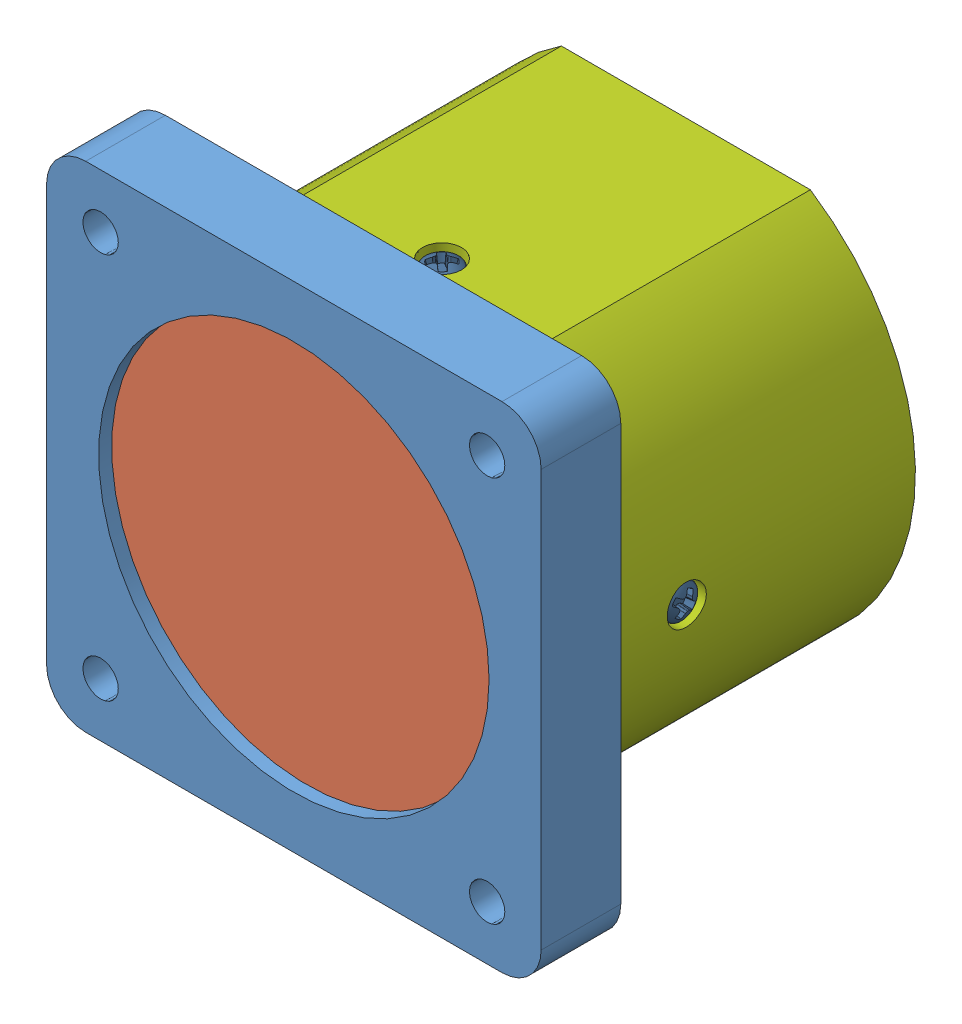
SolidWorks assembly Airspeed Indicator, configuration Default. Lengths in mm.
Overall size (60.32 60.32 47.82).
23 component instances, 13 part files, 54 mates.
Components (placement in the parent):
- Airspeed Indicator Bezel-1: Airspeed Indicator Bezel [Default] at origin size (60.32 60.32 9.72)
- Airspeed Indicator Cover Glass-1: Airspeed Indicator Cover Glass [Default] at (0 0 6.5405) size (49.91 49.91 1.59)
- Airspeed Indicator Dial Face Spacer-1: Airspeed Indicator Dial Face Spacer [Default] at (0 0 1.778) size (49.91 49.91 4.76)
- Airspeed Indicator Dial Face-1: Airspeed Indicator Dial Face [Default] at (0 0 0.1905) size (47.65 47.65 1.59)
- Airspeed Indicator Stepper Mount-1: Airspeed Indicator Stepper Mount [Default] at (0 0 0.1905) x (0 -1 0) z (0 0 -1) size (44.93 49.4 18.35)
- Airspeed Indicator Pointer-1: Airspeed Indicator Pointer [Default] at (0 0 3.3655) x (0.511521 -0.859271 0) z (0 0 1) size (3.17 30.16 0.76)
- Airspeed Indicator Case-1: Airspeed Indicator Case [Connector Down] x (-1 0 0) z (0 0 -1) size (56.01 51.53 38.1)
- VID29-02-1: VID29-02 [Default] at (0 -6 -13.8225) x (-1 0 0) z (0 1 0) size (31.7 22.35 29.3)
- MD-40PL100-1: MD-40PL100 [Default] at (0 0 -34.925) x (0 0 -1) z (1 0 0) size (21.05 14 25)
- 90272A077_ZINC-PLTD STL PAN HEAD PHILLIPS MACHINE SCREW_2-56 X .250-1: 90272A077_ZINC-PLTD STL PAN HEAD PHILLIPS MACHINE SCREW_2-56 X .250 [90272A077] at (-10.0394 -17.3887 -10.2108) x (-0.759966 0.438766 -0.479517) z (-0.5 -0.866025 0) size (4.24 4.24 7.94)
- 90272A077_ZINC-PLTD STL PAN HEAD PHILLIPS MACHINE SCREW_2-56 X .250-4: 90272A077_ZINC-PLTD STL PAN HEAD PHILLIPS MACHINE SCREW_2-56 X .250 [90272A077] at (0 15.6058 -8.3495) x (-0.738734 0 -0.673998) z (0 1 0) size (4.24 4.24 7.94)
- 90272A077_ZINC-PLTD STL PAN HEAD PHILLIPS MACHINE SCREW_2-56 X .250-3: 90272A077_ZINC-PLTD STL PAN HEAD PHILLIPS MACHINE SCREW_2-56 X .250 [90272A077] at (20.0787 0 -10.2108) x (0 0.846222 -0.532831) z (1 0 0) size (4.24 4.24 7.94)
- 93365A110_BRASS HEAT-SET INSERT FOR PLASTICS_2-56-1: 93365A110_BRASS HEAT-SET INSERT FOR PLASTICS_2-56 [Default] at (-12.3508 -21.3921 -10.0203) x (0.855214 -0.493758 -0.157515) z (-0.136412 0.078758 -0.987517) size (3.58 3.09 3.58)
- 93365A110_BRASS HEAT-SET INSERT FOR PLASTICS_2-56-2: 93365A110_BRASS HEAT-SET INSERT FOR PLASTICS_2-56 [Default] at (0 20.2286 -8.3495) x (-0.749902 0 0.661549) z (-0.661549 0 -0.749902) size (3.58 3.09 3.58)
- 93365A110_BRASS HEAT-SET INSERT FOR PLASTICS_2-56-3: 93365A110_BRASS HEAT-SET INSERT FOR PLASTICS_2-56 [Default] at (24.7015 0 -10.0203) x (0 0.487086 -0.873354) z (0 -0.873354 -0.487086) size (3.58 3.09 3.58)
- 93365A102 - INSERT, 0-80, BRASS, FOR PLASTICS-1: 93365A102 - INSERT, 0-80, BRASS, FOR PLASTICS [Default] at (-13.5 -6 -7.1105) x (0 1 0) z (-1 0 0) size (3.58 3.01 3.58)
- 93365A102 - INSERT, 0-80, BRASS, FOR PLASTICS-2: 93365A102 - INSERT, 0-80, BRASS, FOR PLASTICS [Default] at (13.5 -6 -7.1105) x (-0.158553 0.987351 0) z (-0.987351 -0.158553 0) size (3.58 3.01 3.58)
- 91772A064 - PHS, 0-80 x .4375, 18-8-1: 91772A064 - PHS, 0-80 x .4375, 18-8 [91772A064] at (-13.5 -6 -3.01) x (-1 0 0) z (0 0 -1) size (2.95 2.95 12.24)
- 91772A064 - PHS, 0-80 x .4375, 18-8-2: 91772A064 - PHS, 0-80 x .4375, 18-8 [91772A064] at (13.5 -6 -3.01) x (-0.987351 -0.158553 0) z (0 0 -1) size (2.95 2.95 12.24)
- 93365A102 - INSERT, 0-80, BRASS, FOR PLASTICS-4: 93365A102 - INSERT, 0-80, BRASS, FOR PLASTICS [Default] at (-9.5 0 -34.925) x (-0.015308 0.999883 0) z (0.999883 0.015308 0) size (3.58 3.01 3.58)
- 93365A102 - INSERT, 0-80, BRASS, FOR PLASTICS-6: 93365A102 - INSERT, 0-80, BRASS, FOR PLASTICS [Default] at (9.5 0 -34.925) x (-0.188703 0.982034 0) z (0.982034 0.188703 0) size (3.58 3.01 3.58)
- 91772A064 - PHS, 0-80 x .4375, 18-8-4: 91772A064 - PHS, 0-80 x .4375, 18-8 [91772A064] at (-9.5 0 -38.0375) x (-0.949722 0.313094 0) z (0 0 1) size (2.95 2.95 12.24)
- 91772A064 - PHS, 0-80 x .4375, 18-8-6: 91772A064 - PHS, 0-80 x .4375, 18-8 [91772A064] at (9.5 0 -38.0375) x (-0.902124 0.431476 0) z (0 0 1) size (2.95 2.95 12.24)
Mates (geometry in assembly coordinates):
- InPlace1: in place: plane of Airspeed Indicator Bezel-1 through (0 0 0) normal (0 0 1); moOrthogonalPlaneRef_w of Airspeed Indicator Bezel-1 through (0 0 0) normal (0 1 0); plane of Airspeed Indicator Bezel-1 through (0 0 0) normal (1 0 0); unknown of Airspeed Indicator Bezel-1
- Coincident1: coincident: plane of Airspeed Indicator Bezel-1; plane of assembly
- Coincident2: coincident: plane of Airspeed Indicator Bezel-1 through (0 0 0) normal (0 1 0); moOrthogonalPlaneRef_w of assembly
- Coincident3: coincident: plane of Airspeed Indicator Bezel-1 through (0 0 0) normal (1 0 0); moOrthogonalPlaneRef_w of assembly
- Concentric1: concentric: cylinder of Airspeed Indicator Bezel-1 through (0 0 81.3779) axis (0 0 -1) radius 25.3365; cylinder of Airspeed Indicator Cover Glass-1 through (0 0 8.128) axis (0 0 -1) radius 24.9555
- Coincident1: coincident: plane of Airspeed Indicator Bezel-1 through (0 0 8.128) normal (0 0 -1); plane of Airspeed Indicator Cover Glass-1 through (0 0 8.128) normal (0 0 1)
- Concentric2: concentric: cylinder of Airspeed Indicator Bezel-1 through (0 0 81.3779) axis (0 0 -1) radius 25.3365; cylinder of Airspeed Indicator Dial Face Spacer-1 through (0 0 6.5405) axis (0 0 -1) radius 24.9555
- Coincident2: coincident: plane of Airspeed Indicator Cover Glass-1 through (0 0 6.5405) normal (0 0 -1); plane of Airspeed Indicator Dial Face Spacer-1 through (0 0 6.5405) normal (0 0 1)
- Concentric5: concentric: cylinder of Airspeed Indicator Bezel-1 through (0 0 81.3779) axis (0 0 -1) radius 25.3365; cylinder of Airspeed Indicator Dial Face-1 through (0 0 1.778) axis (0 0 -1) radius 23.8252
- Parallel1: parallel: plane of Airspeed Indicator Bezel-1 through (30.1625 0 9.7155) normal (1 0 0); plane of Airspeed Indicator Dial Face-1 through (0 0 0.1905) normal (1 0 0)
- Concentric9: concentric: cylinder of Airspeed Indicator Bezel-1 through (0 0 81.3779) axis (0 0 -1) radius 25.3365; cylinder of Airspeed Indicator Stepper Mount-1 through (0 0 -72.238) axis (0 0 1) radius 24.7015
- Coincident7: coincident: plane of Airspeed Indicator Dial Face-1 through (0 0 0.1905) normal (0 0 -1); plane of Airspeed Indicator Stepper Mount-1 through (0 0 0.1905) normal (0 0 1)
- Parallel2: parallel: plane of Airspeed Indicator Bezel-1 through (0 30.1625 9.7155) normal (0 1 0); plane of Airspeed Indicator Stepper Mount-1 through (0 0 0.1905) normal (0 -1 0)
- Distance1: distance = 1.5875 mm: plane of Airspeed Indicator Pointer-1 through (0 0 3.3655) normal (0 0 -1); plane of Airspeed Indicator Dial Face-1 through (0 0 1.778) normal (0 0 1)
- Coincident13: coincident: plane of Airspeed Indicator Dial Face Spacer-1 through (0 0 1.778) normal (0 0 -1); plane of Airspeed Indicator Dial Face-1 through (0 0 1.778) normal (0 0 1)
- InPlace2: in place: plane of Airspeed Indicator Bezel-1 through (0 0 1.5875) normal (0 0 -1); plane of ? through (0 0 1.5875) normal (0 0 -1); plane of Airspeed Indicator Bezel-1 through (0 0 1.5875) normal (0 0 -1); unknown of ?; plane of Airspeed Indicator Bezel-1 through (0 0 1.5875) normal (0 0 -1); plane of ? through (0 0 1.5875) normal (-1 0 0); plane of Airspeed Indicator Bezel-1 through (0 0 0) normal (0 0 -1); unknown of Airspeed Indicator Case-1
- Coincident14: coincident: plane of Airspeed Indicator Bezel-1; plane of Airspeed Indicator Case-1
- Coincident15: coincident: moOrthogonalPlaneRef_w of Airspeed Indicator Bezel-1 through (0 0 0) normal (0 1 0); plane of Airspeed Indicator Case-1 through (0 0 0) normal (0 1 0)
- Coincident16: coincident: moOrthogonalPlaneRef_w of Airspeed Indicator Bezel-1 through (0 0 0) normal (1 0 0); plane of Airspeed Indicator Case-1 through (0 0 0) normal (-1 0 0)
- Concentric43: concentric: cylinder of Airspeed Indicator Case-1 through (-14.0017 -24.2517 -10.2108) axis (-0.5 -0.866025 0) radius 2.3813; cylinder of 90272A077_ZINC-PLTD STL PAN HEAD PHILLIPS MACHINE SCREW_2-56 X .250-1 through (-10.0394 -17.3887 -10.2108) axis (0.5 0.866025 0) radius 2.1209
- Coincident55: coincident: plane of Airspeed Indicator Case-1 through (-13.2143 -22.8879 -11.5633) normal (-0.5 -0.866025 0); plane of 90272A077_ZINC-PLTD STL PAN HEAD PHILLIPS MACHINE SCREW_2-56 X .250-1 through (-13.2143 -22.8879 -10.2108) normal (0.5 0.866025 0)
- Concentric44: concentric: cylinder of Airspeed Indicator Case-1 through (0 23.5306 -8.3495) axis (0 1 0) radius 2.3813; cylinder of 90272A077_ZINC-PLTD STL PAN HEAD PHILLIPS MACHINE SCREW_2-56 X .250-4 through (0 15.6058 -8.3495) axis (0 -1 0) radius 2.1209
- Coincident56: coincident: plane of Airspeed Indicator Case-1 through (-1.3526 21.9558 -8.3495) normal (0 1 0); plane of 90272A077_ZINC-PLTD STL PAN HEAD PHILLIPS MACHINE SCREW_2-56 X .250-4 through (0 21.9558 -8.3495) normal (0 -1 0)
- Coincident57: coincident: plane of Airspeed Indicator Case-1 through (26.4287 1.3526 -10.2108) normal (1 0 0); plane of 90272A077_ZINC-PLTD STL PAN HEAD PHILLIPS MACHINE SCREW_2-56 X .250-3 through (26.4287 0 -10.2108) normal (-1 0 0)
- Concentric46: concentric: cone of Airspeed Indicator Stepper Mount-1 through (-12.3508 -21.3921 -10.0203) axis (0.5 0.866025 0); cone of 93365A110_BRASS HEAT-SET INSERT FOR PLASTICS_2-56-1 through (-11.7958 -20.4309 -10.0203) axis (0.5 0.866025 0)
- Coincident58: coincident: plane of Airspeed Indicator Stepper Mount-1 through (-12.3508 -21.3921 -10.0203) normal (-0.5 -0.866025 0); plane of 93365A110_BRASS HEAT-SET INSERT FOR PLASTICS_2-56-1 through (-13.8822 -20.508 -9.7382) normal (-0.5 -0.866025 0)
- Concentric47: concentric: cone of Airspeed Indicator Stepper Mount-1 through (0 20.2286 -8.3495) axis (0 -1 0); cone of 93365A110_BRASS HEAT-SET INSERT FOR PLASTICS_2-56-2 through (0 19.1186 -8.3495) axis (0 -1 0)
- Concentric48: concentric: cone of Airspeed Indicator Stepper Mount-1 through (24.7015 0 -10.0203) axis (-1 0 0); cone of 93365A110_BRASS HEAT-SET INSERT FOR PLASTICS_2-56-3 through (23.5915 0 -10.0203) axis (-1 0 0)
- Coincident60: coincident: plane of Airspeed Indicator Stepper Mount-1 through (24.7015 0 -10.0203) normal (1 0 0); plane of 93365A110_BRASS HEAT-SET INSERT FOR PLASTICS_2-56-3 through (24.7015 -0.8722 -8.4564) normal (1 0 0)
- Concentric49: concentric: cylinder of Airspeed Indicator Dial Face-1 through (0 0 0.1905) axis (0 0 1) radius 0.7937; cylinder of VID29-02-1 through (0 0 -7.4225) axis (0 0 -1) radius 0.5
- Coincident61: coincident: plane of Airspeed Indicator Pointer-1 through (0 0 4.1275) normal (0 0 1); plane of VID29-02-1 through (0 0 4.1275) normal (0 0 1)
- Concentric50: concentric: cone of Airspeed Indicator Stepper Mount-1 through (-13.5 -6 -7.1105) axis (0 0 1); cone of 93365A102 - INSERT, 0-80, BRASS, FOR PLASTICS-1 through (-13.5 -6 -6.0005) axis (0 0 1)
- Coincident62: coincident: plane of Airspeed Indicator Stepper Mount-1 through (-13.5 -6 -7.1105) normal (0 0 -1); plane of 93365A102 - INSERT, 0-80, BRASS, FOR PLASTICS-1 through (-13.5 -7.7907 -7.1105) normal (0 0 -1)
- Concentric51: concentric: cone of Airspeed Indicator Stepper Mount-1 through (13.5 -6 -7.1105) axis (0 0 1); cone of 93365A102 - INSERT, 0-80, BRASS, FOR PLASTICS-2 through (13.5 -6 -6.0005) axis (0 0 1)
- Coincident63: coincident: plane of Airspeed Indicator Stepper Mount-1 through (13.5 -6 -7.1105) normal (0 0 -1); plane of 93365A102 - INSERT, 0-80, BRASS, FOR PLASTICS-2 through (13.7839 -7.768 -7.1105) normal (0 0 -1)
- Concentric52: concentric: cylinder of Airspeed Indicator Dial Face-1 through (0 0 0.1905) axis (0 0 1) radius 0.7937; cylinder of Airspeed Indicator Pointer-1 through (0 0 4.1275) axis (0 0 -1) radius 0.5
- Concentric53: concentric: cylinder of VID29-02-1 through (-13.5 -6 -14.1225) axis (0 0 -1) radius 0.925; cylinder of 91772A064 - PHS, 0-80 x .4375, 18-8-1 through (-13.5 -6 -3.01) axis (0 0 1) radius 1.4732
- Coincident64: coincident: plane of VID29-02-1 through (0 -6 -14.1225) normal (0 0 -1); plane of 91772A064 - PHS, 0-80 x .4375, 18-8-1 through (-13.5 -6 -14.1225) normal (0 0 1)
- Concentric54: concentric: cylinder of VID29-02-1 through (13.5 -6 -14.1225) axis (0 0 -1) radius 0.925; cylinder of 91772A064 - PHS, 0-80 x .4375, 18-8-2 through (13.5 -6 -3.01) axis (0 0 1) radius 1.4732
- Coincident65: coincident: plane of VID29-02-1 through (0 -6 -14.1225) normal (0 0 -1); plane of 91772A064 - PHS, 0-80 x .4375, 18-8-2 through (13.5 -6 -14.1225) normal (0 0 1)
- Concentric55: concentric: cylinder of Airspeed Indicator Stepper Mount-1 through (0 0 -72.238) axis (0 0 1) radius 24.7015; cylinder of MD-40PL100-1 through (0 0 -21.725) axis (0 0 -1) radius 6
- Parallel4: parallel: plane of Airspeed Indicator Bezel-1 through (0 30.1625 9.7155) normal (0 1 0); plane of MD-40PL100-1 through (-3.3166 5 -25.725) normal (0 1 0)
- Coincident66: coincident: plane of Airspeed Indicator Case-1 through (0 0 -34.925) normal (0 0 1); plane of MD-40PL100-1 through (0 0 -34.925) normal (0 0 -1)
- Concentric56: concentric: cone of Airspeed Indicator Case-1 through (-9.5 0 -34.925) axis (0 0 -1); cone of 93365A102 - INSERT, 0-80, BRASS, FOR PLASTICS-4 through (-9.5 0 -36.035) axis (0 0 -1)
- Coincident67: coincident: plane of Airspeed Indicator Case-1 through (0 0 -34.925) normal (0 0 1); plane of 93365A102 - INSERT, 0-80, BRASS, FOR PLASTICS-4 through (-9.4726 -1.7905 -34.925) normal (0 0 1)
- Concentric57: concentric: cone of Airspeed Indicator Case-1 through (9.5 0 -34.925) axis (0 0 -1); cone of 93365A102 - INSERT, 0-80, BRASS, FOR PLASTICS-6 through (9.5 0 -36.035) axis (0 0 -1)
- Coincident68: coincident: plane of Airspeed Indicator Case-1 through (0 0 -34.925) normal (0 0 1); plane of 93365A102 - INSERT, 0-80, BRASS, FOR PLASTICS-6 through (9.8379 -1.7585 -34.925) normal (0 0 1)
- Concentric58: concentric: cylinder of MD-40PL100-1 through (-9.5 0 -21.6477) axis (0 0 -1) radius 1.05; cylinder of 91772A064 - PHS, 0-80 x .4375, 18-8-4 through (-9.5 0 -38.0375) axis (0 0 -1) radius 1.4732
- Coincident69: coincident: plane of MD-40PL100-1 through (-9.5 0 -26.925) normal (0 0 1); plane of 91772A064 - PHS, 0-80 x .4375, 18-8-4 through (-9.5 0 -26.925) normal (0 0 -1)
- Concentric59: concentric: cylinder of MD-40PL100-1 through (9.5 0 -21.6477) axis (0 0 -1) radius 1.05; cylinder of 91772A064 - PHS, 0-80 x .4375, 18-8-6 through (9.5 0 -38.0375) axis (0 0 -1) radius 1.4732
- Coincident70: coincident: plane of MD-40PL100-1 through (9.5 0 -26.925) normal (0 0 1); plane of 91772A064 - PHS, 0-80 x .4375, 18-8-6 through (9.5 0 -26.925) normal (0 0 -1)
- Parallel6: parallel: plane of Airspeed Indicator Stepper Mount-1 through (14.1764 20.2286 -72.238) normal (0 1 0); plane of VID29-02-1 through (4.5288 -20.3 -7.4225) normal (0 -1 0)
- Coincident71: coincident: plane of Airspeed Indicator Stepper Mount-1 through (14.1764 20.2286 -72.238) normal (0 1 0); plane of 93365A110_BRASS HEAT-SET INSERT FOR PLASTICS_2-56-2 through (1.3428 20.2286 -9.5341) normal (0 1 0)
- Concentric60: concentric: cylinder of Airspeed Indicator Case-1 through (28.0035 0 -10.2108) axis (1 0 0) radius 2.3813; cylinder of 90272A077_ZINC-PLTD STL PAN HEAD PHILLIPS MACHINE SCREW_2-56 X .250-3 through (20.0787 0 -10.2108) axis (-1 0 0) radius 2.1209
